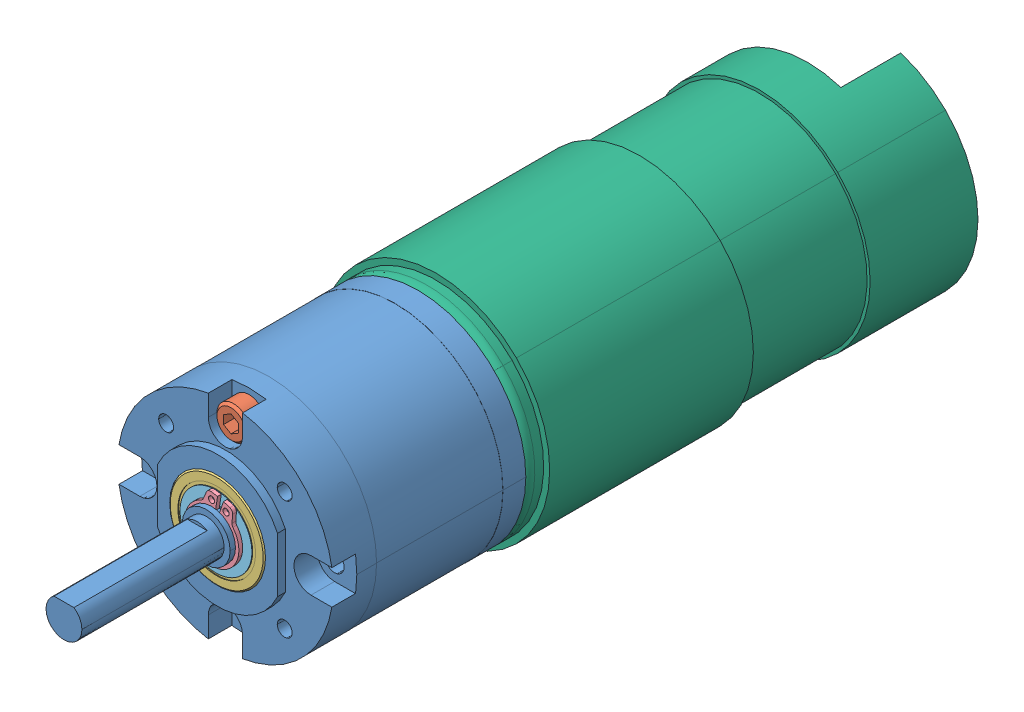
SolidWorks assembly Motor, configuration Default. Lengths in mm.
Overall size (53.74 53.74 85.19).
9 component instances, 6 part files, 0 mates.
Components (placement in the parent):
- NeveRest orbital 2 stage Gearbox.STEP-1: NeveRest orbital 2 stage Gearbox.STEP [Default] at (-28.8441 -12.442 -2.3383) size (36 36 59.11) (hidden)
- SHCS M3 x 16mm.STEP-1: SHCS M3 x 16mm.STEP [Default] at (-28.8441 1.8455 25.8811) size (5.5 5.5 19) (hidden)
- SHCS M3 x 16mm.STEP-2: SHCS M3 x 16mm.STEP [Default] at (-14.5566 -12.442 25.8811) x (0 -1 0) z (0 0 1) size (5.5 5.5 19) (hidden)
- SHCS M3 x 16mm.STEP-3: SHCS M3 x 16mm.STEP [Default] at (-28.8441 -26.7295 25.8811) x (-1 0 0) z (0 0 1) size (5.5 5.5 19) (hidden)
- SHCS M3 x 16mm.STEP-4: SHCS M3 x 16mm.STEP [Default] at (-43.1316 -12.442 25.8811) x (0 1 0) z (0 0 1) size (5.5 5.5 19) (hidden)
- 7804K117_STAINLESS STEEL BALL BEARING_7804K117.STEP-1: 7804K117_STAINLESS STEEL BALL BEARING_7804K117.STEP [Default] at (-28.8441 -12.442 28.7705) x (0.941717 0.336405 0) z (0 0 1) size (16 16 5) (hidden)
- 97633A150_BLACK-FINISH STEEL EXTERNAL RETAINING RING_97633A150_grv.STEP-1: 97633A150_BLACK-FINISH STEEL EXTERNAL RETAINING RING_97633A150_grv.STEP [Default] at (-28.8441 -12.442 31.715) x (0 0 -1) z (0.971339 -0.2377 0) size (0.64 10.57 9.01) (hidden)
- Shim.STEP-1: Shim.STEP [Default] at (-28.8441 -12.442 31.3975) x (1 0 0) z (0 1 0) size (12 0.13 12) (hidden)
- am-3104 NeveRest Motor.STEP-1: am-3104 NeveRest Motor.STEP [Default] at (-28.8441 -12.442 -2.3303) x (0.707107 0.707107 0) z (0 0 1) size (38 38 85.19)
